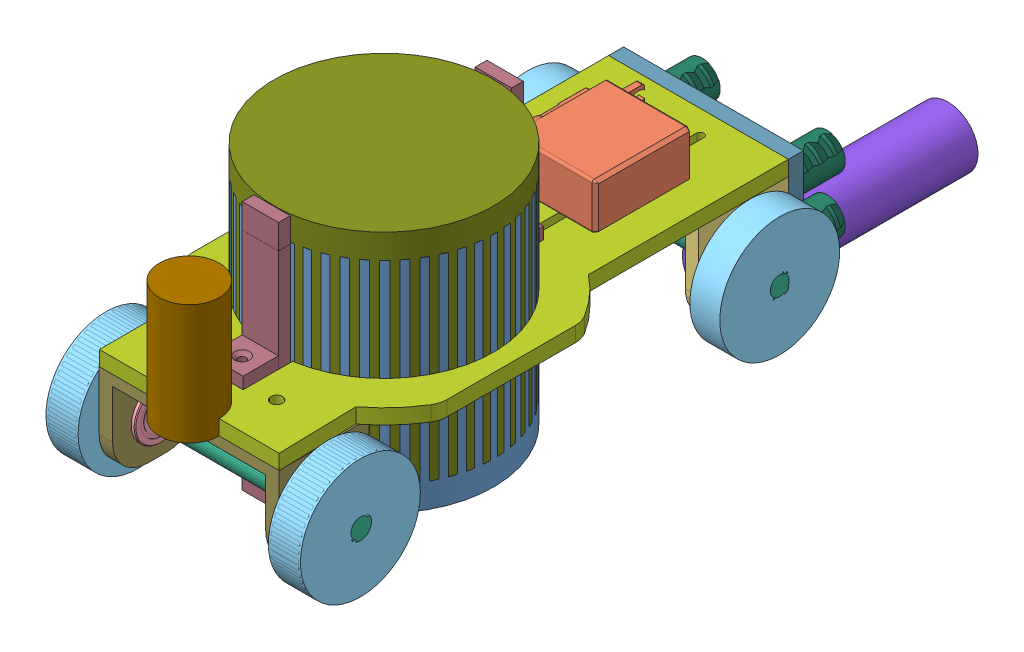
SolidWorks assembly Assem1, configuration Default. Lengths in mm.
Overall size (112.29 129.46 336.69).
37 component instances, 16 part files, 0 mates.
Components (placement in the parent):
- Probe Master-1: Probe Master [Default] at (-123.831 -91.2743 -133.463) size (108.55 129.46 336.69)
  - battery jar v1-1: battery jar v1 [Default] at (59.4741 87.4697 192.7195) x (0.971724 0 0.23612) z (-0.23612 0 0.971724) size (92.96 92.84 92.96)
  - Servo-1: Servo [預設] at (57.8734 136.9878 87.6912) x (0 0 1) z (0 -1 0) size (54.5 43.19 19.5)
  - Wheel Holder-1: Wheel Holder [Default] at (20.8564 86.5995 97.4695) x (-1 0 0) z (0 0 -1) size (76.2 40.01 38.1)
  - STAINLESS STEEL BALL BEARING-2: STAINLESS STEEL BALL BEARING [6138K66] at (95.5579 107.7778 78.4195) x (0 -0.802943 -0.596056) z (-1 0 0) size (22.23 22.23 7.14)
  - STAINLESS STEEL BALL BEARING-3: STAINLESS STEEL BALL BEARING [6138K66] at (24.9459 107.7778 78.4195) x (0 -0.922928 -0.384973) z (-1 0 0) size (22.23 22.23 7.14)
  - Wheel-1: Wheel [Default] at (18.6741 107.7778 78.4195) x (0 0.988152 -0.153476) z (-1 0 0) size (50.8 50.8 12.7)
  - STAINLESS STEEL BALL BEARING-4: STAINLESS STEEL BALL BEARING [6138K66] at (94.0022 107.7778 256.2195) x (0 0 -1) z (1 0 0) size (22.23 22.23 7.14)
  - STAINLESS STEEL BALL BEARING-5: STAINLESS STEEL BALL BEARING [6138K66] at (24.9459 107.7778 256.2195) x (0 0 1) z (-1 0 0) size (22.23 22.23 7.14)
  - real axel-2: real axel [Default] at (112.9741 107.7778 256.2195) x (0 -0.781777 -0.623558) z (-1 0 0) size (9.53 9.53 107)
  - Wheel-2: Wheel [Default] at (5.9741 107.7778 256.2195) x (0 0.027995 -0.999608) z (1 0 0) size (50.8 50.8 12.7)
  - Wheel-3: Wheel [Default] at (100.2741 107.7778 256.2195) x (0 0.063776 -0.997964) z (1 0 0) size (50.8 50.8 12.7)
  - Vertical Base-1: Vertical Base [Default] at (51.2333 130.6378 192.9855) size (107.95 6.35 215.9)
  - real axel-3: real axel [Default] at (112.9741 107.7778 78.4195) x (0 -0.930183 0.367096) z (-1 0 0) size (9.53 9.53 107)
  - Wheel-4: Wheel [Default] at (112.9741 107.7778 78.4195) x (0 -0.03437 -0.999409) z (-1 0 0) size (50.8 50.8 12.7)
  - Sediment Sample-1: Sediment Sample [Default] at (60.2269 74.1232 -45.7105) x (1 0 0) z (0 -1 0) size (25.4 100 25.4)
  - 2in_len_half_in_pvc-1: 2in_len_half_in_pvc [Default] at (59.4741 130.6378 275.2695) size (25.4 50.8 25.4)
  - GearServo-2: GearServo [Default] at (55.5578 139.3555 114.3654) x (0 0 1) z (-1 0 0) size (13.63 13.64 3.73)
    - gearServo part1-1: gearServo part1 [Default] at (40.1786 -28.1141 10.1283) size (8.5 8.53 3.23)
    - gearServo part 2-1: gearServo part 2 [Default] at (4.0729 7.3684 9.8743) size (13.59 13.59 0.25)
    - gearServo part 2-2: gearServo part 2 [Default] at (4.0343 7.4237 13.3541) size (13.59 13.59 0.25)
  - Wheel Holder_Back-1: Wheel Holder_Back [Default] at (97.997 86.5995 237.1695) size (76.2 40.01 38.1)
  - CageV3-1: CageV3 [Default] at (51.2808 84.9697 140.8315) x (0 0 1) z (-1 0 0) size (118.8 95.5 34)
  - springwall-1: springwall [Default] at (21.3741 136.9878 59.3695) x (1 0 0) z (0 0 -1) size (76.2 51.56 6.35)
  - spring barb-1: spring barb [Default] at (85.9861 96.4258 53.0195) x (-0.781154 -0.624339 0) z (0.624339 -0.781154 0) size (20.52 21.79 15.18)
  - spring barb-2: spring barb [Default] at (85.9861 120.1878 53.0195) x (-0.577939 -0.81608 0) z (0.81608 -0.577939 0) size (20.52 21.79 15.18)
  - spring barb-3: spring barb [Default] at (32.9621 96.4258 53.0195) x (-0.781154 -0.624339 0) z (0.624339 -0.781154 0) size (20.52 21.79 15.18)
  - spring barb-4: spring barb [Default] at (32.9621 120.1878 53.0195) x (-0.664278 -0.747485 0) z (0.747485 -0.664278 0) size (20.52 21.79 15.18)
  - Wheel Holder_Back-2: Wheel Holder_Back [Default] at (98.0917 86.5995 237.1695) size (76.2 40.01 38.1)
  - Battery Jar-1: Battery Jar [Default] at (59.4741 97.8466 192.7195) x (0.983461 0 -0.181118) z (0.181118 0 0.983461) size (92.96 92.84 92.96)
  - real axel-4: real axel [Default] at (5.202 107.7778 78.4195) x (0 -0.35628 -0.934379) z (1 0 0) size (9.53 9.53 107)
  - STAINLESS STEEL BALL BEARING-6: STAINLESS STEEL BALL BEARING [6138K66] at (24.9459 107.7778 256.2195) x (0 0 1) z (-1 0 0) size (22.23 22.23 7.14)
  - STAINLESS STEEL BALL BEARING-7: STAINLESS STEEL BALL BEARING [6138K66] at (94.0022 107.7778 256.2195) x (0 -0.258337 -0.966055) z (1 0 0) size (22.23 22.23 7.14)
  - Wheel-5: Wheel [Default] at (17.7536 107.7778 256.2195) x (0 -0.862637 0.505823) z (-1 0 0) size (50.8 50.8 12.7)
  - Wheel-6: Wheel [Default] at (112.0536 107.7778 256.2195) x (0 -0.070162 0.997536) z (-1 0 0) size (50.8 50.8 12.7)
  - real axel-5: real axel [Default] at (5.0536 107.7778 256.2195) x (0 0.102337 -0.99475) z (1 0 0) size (9.53 9.53 107)
  - CageV3-3: CageV3 [Default] at (51.2333 95.3878 140.8076) x (0 0 1) z (-1 0 0) size (118.8 95.5 34)
